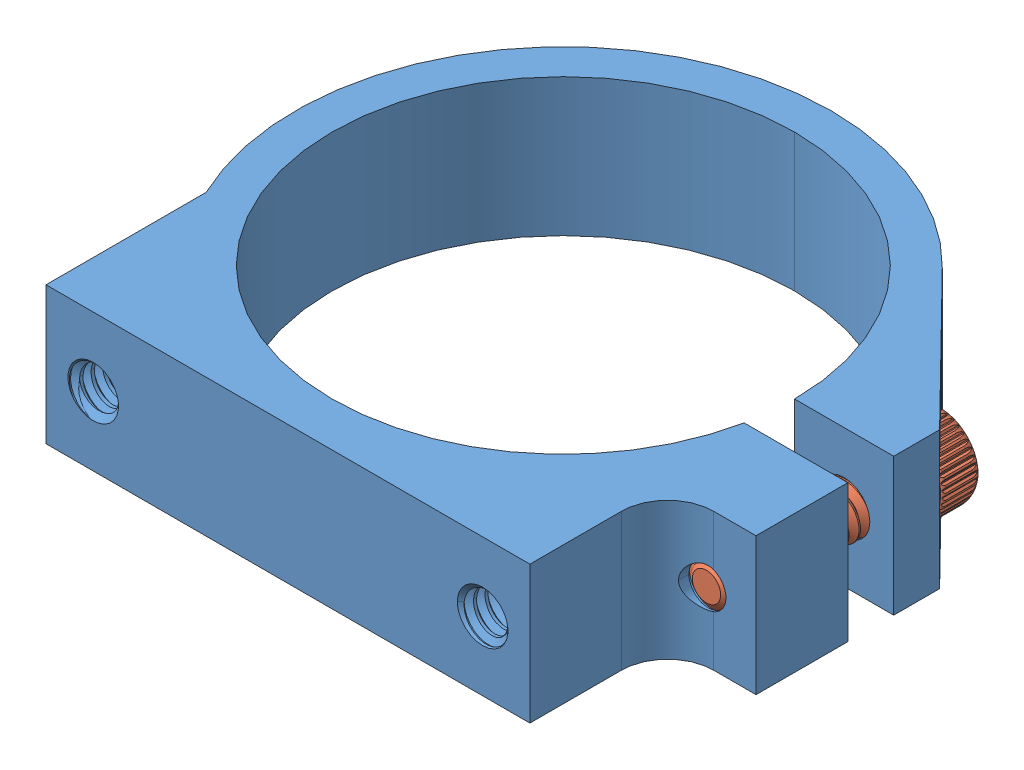
SolidWorks assembly 555176 assembly, configuration Default. Lengths in mm.
Overall size (41.83 9.53 37.59).
2 component instances, 2 part files, 0 mates.
Components (placement in the parent):
- 555176.STEP-1: 555176.STEP [Default] at (-66.8841 14.913 20.3951) size (41.4 9.53 37.59)
- 632114_90128A121.STEP-1: 632114_90128A121.STEP [Default] at (-47.4551 19.6755 55.3201) x (0.529697 -0.848187 0) z (0 0 1) size (5.61 5.61 16.21)
